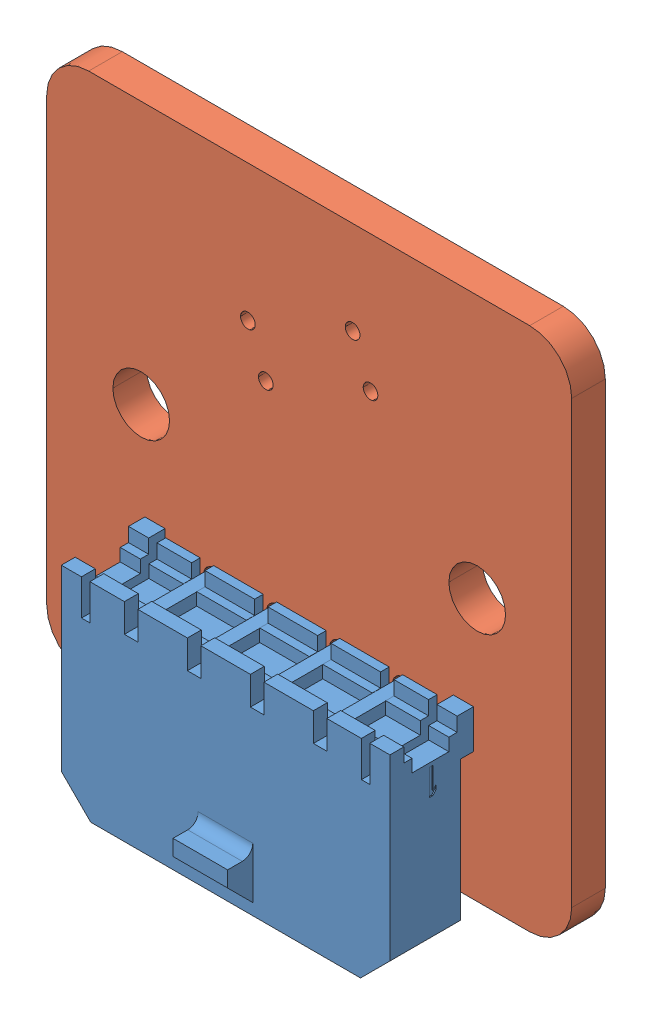
SolidWorks assembly IR Sensor Board.STEP, configuration Default. Lengths in mm.
Overall size (25 26.95 8.91).
4 component instances, 2 part files, 0 mates.
Components (placement in the parent):
- IR Sensor Board.step.STEP-1: IR Sensor Board.step.STEP [Default] at origin size (25 26.95 8.91)
  - 43650-0400.step.STEP-1: 43650-0400.step.STEP [Default] at (32.5 -42 3.65) x (1 0 0) z (0 -1 0) size (15.65 8.91 9.9)
    - COMPOUND.step.STEP-1: COMPOUND.step.STEP [Default] at origin size (15.65 8.91 9.9)
  - IR Sensor Board PCB.step.STEP-1: IR Sensor Board PCB.step.STEP [Default] at origin size (25 25 1.6)
